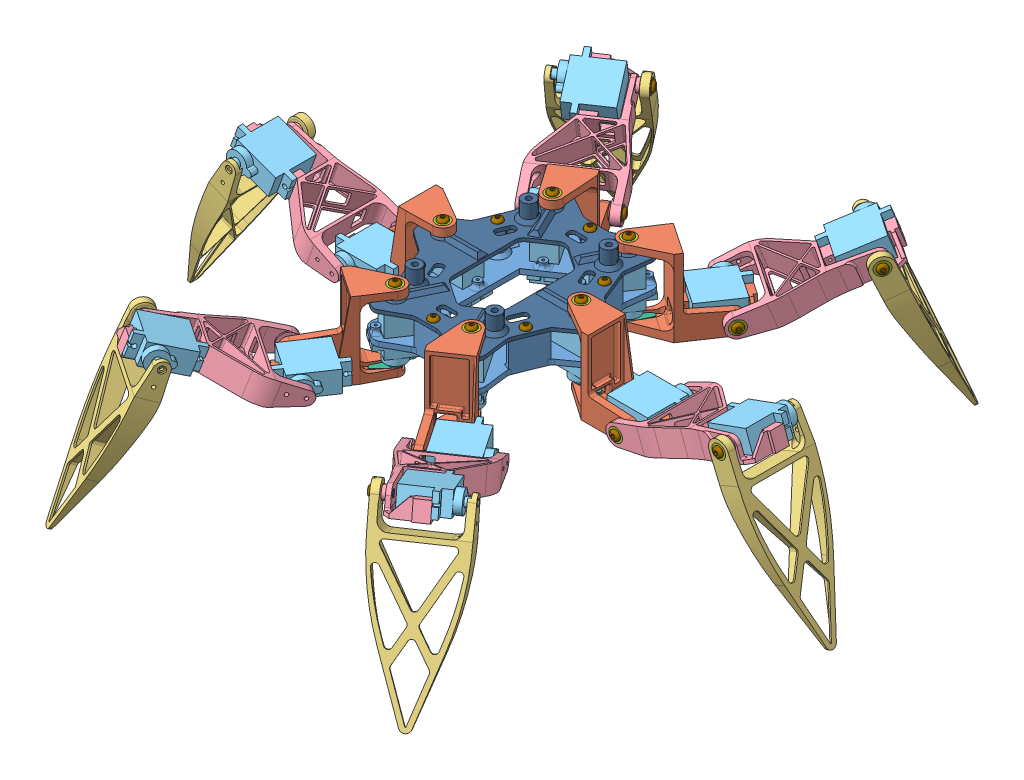
SolidWorks assembly Assem1, configuration Default. Lengths in mm.
Overall size (377.21 111.85 364.23).
104 component instances, 10 part files, 33 mates.
Components (placement in the parent):
- Base-1: Base [Default] at (36.3736 62.9905 92.2732) size (103.38 17 115.92)
- leg-1: leg [Default] at (45.8223 35.6523 69.1252) size (170.91 110.5 47.15)
  - hip-1: hip [Default] at (51.2432 8.3382 17.148) size (59.75 45 23)
  - shin-1: shin [Default] at (173.3847 -53.1633 22.948) x (0 0 1) z (-0.920457 -0.390844 0) size (45 106 12.27)
  - thigh-1: thigh [Default] at (116.4644 23.5871 17.948) x (0.93934 0.342988 0) z (0 0 1) size (82.75 14 45)
  - MG90S Servo-1: MG90S Servo [Default] at (129.6036 37.1675 33.948) x (0.93934 0.342988 0) z (-0.342988 0.93934 0) size (34 31 12.5)
  - MG90S Servo-2: MG90S Servo [Default] at (68.2432 16.5882 33.148) x (1 0 0) z (0 1 0) size (34 31 12.5)
  - MG90S Servo-4: MG90S Servo [Default] at (25.2432 43.3382 23.148) x (1 0 0) z (0 0 -1) size (34 31 12.5)
  - servo horn-1: servo horn [Default] at (31.2432 10.8382 23.148) size (14.5 4.5 6)
  - Bearing-1: Bearing [Default] at (73.2432 16.5882 40.948) x (1 0 0) z (0 -1 0) size (8 4 8)
  - threaded insert-1: threaded insert [Default] at (73.2432 16.5882 35.448) x (1 0 0) z (0 -1 0) size (4 4.7 4)
  - threaded insert-2: threaded insert [Default] at (134.3003 38.8824 36.248) x (0.987351 0.158553 0) z (0.158553 -0.987351 0) size (4 4.7 4)
  - Bearing-2: Bearing [Default] at (31.2432 49.3382 23.148) x (0.930301 0 -0.366796) z (0.366796 0 0.930301) size (8 4 8)
  - Bearing-5: Bearing [Default] at (134.3003 38.8824 41.448) x (0.766992 0.641657 0) z (0.641657 -0.766992 0) size (8 4 8)
  - m3x8 button-1: m3x8 button [Default] at (73.2432 16.5882 46.598) x (0 0 -1) z (0.234843 0.972033 0) size (9.65 5.7 5.7)
  - m3x8 button-2: m3x8 button [Default] at (134.3003 38.8824 47.098) x (0 0 -1) z (0.077754 0.996973 0) size (9.65 5.7 5.7)
  - m3x8 button-4: m3x8 button [Default] at (31.2432 54.9882 23.148) x (0 -1 0) z (-0.515031 0 -0.857172) size (9.65 5.7 5.7)
- Top-1: Top [Default] at (36.3236 79.9905 92.3982) size (103.88 12 115.92)
- m3x8 button-1: m3x8 button [Default] at (67.7613 83.6405 115.5337) x (0 -1 0) z (-0.034129 0 0.999417) size (9.65 5.7 5.7)
- m3x8 button-2: m3x8 button [Default] at (36.3236 83.6405 138.3982) x (0 -1 0) z (0.154828 0 0.987941) size (9.65 5.7 5.7)
- m3x8 button-3: m3x8 button [Default] at (4.8859 83.6405 115.5337) x (0 -1 0) z (0.364161 0 0.931336) size (9.65 5.7 5.7)
- m3x8 button-4: m3x8 button [Default] at (4.8859 83.6405 69.2627) x (0 -1 0) z (0.572348 0 0.820011) size (9.65 5.7 5.7)
- m3x8 button-5: m3x8 button [Default] at (36.3236 83.6405 46.3982) x (0 -1 0) z (0.751604 0 0.659615) size (9.65 5.7 5.7)
- m3x8 button-6: m3x8 button [Default] at (67.7613 83.6405 69.2627) x (0 -1 0) z (0.880548 0 0.473957) size (9.65 5.7 5.7)
- leg-2: leg [Default] at (60.4579 35.6523 99.6313) x (0.560629 0 0.828067) z (-0.828067 0 0.560629) size (170.91 110.5 47.15)
  - hip-1: hip [Default] at (51.2432 8.3382 17.148) size (59.75 45 23)
  - shin-1: shin [Default] at (173.3847 -53.1633 22.948) x (0 0 1) z (-0.920457 -0.390844 0) size (45 106 12.27)
  - thigh-1: thigh [Default] at (116.4644 23.5871 17.948) x (0.93934 0.342988 0) z (0 0 1) size (82.75 14 45)
  - MG90S Servo-1: MG90S Servo [Default] at (129.6036 37.1675 33.948) x (0.93934 0.342988 0) z (-0.342988 0.93934 0) size (34 31 12.5)
  - MG90S Servo-2: MG90S Servo [Default] at (68.2432 16.5882 33.148) x (1 0 0) z (0 1 0) size (34 31 12.5)
  - MG90S Servo-4: MG90S Servo [Default] at (25.2432 43.3382 23.148) x (1 0 0) z (0 0 -1) size (34 31 12.5)
  - servo horn-1: servo horn [Default] at (31.2432 10.8382 23.148) size (14.5 4.5 6)
  - Bearing-1: Bearing [Default] at (73.2432 16.5882 40.948) x (1 0 0) z (0 -1 0) size (8 4 8)
  - threaded insert-1: threaded insert [Default] at (73.2432 16.5882 35.448) x (1 0 0) z (0 -1 0) size (4 4.7 4)
  - threaded insert-2: threaded insert [Default] at (134.3003 38.8824 36.248) x (0.987351 0.158553 0) z (0.158553 -0.987351 0) size (4 4.7 4)
  - Bearing-2: Bearing [Default] at (31.2432 49.3382 23.148) x (0.930301 0 -0.366796) z (0.366796 0 0.930301) size (8 4 8)
  - Bearing-5: Bearing [Default] at (134.3003 38.8824 41.448) x (0.766992 0.641657 0) z (0.641657 -0.766992 0) size (8 4 8)
  - m3x8 button-1: m3x8 button [Default] at (73.2432 16.5882 46.598) x (0 0 -1) z (0.234843 0.972033 0) size (9.65 5.7 5.7)
  - m3x8 button-2: m3x8 button [Default] at (134.3003 38.8824 47.098) x (0 0 -1) z (0.077754 0.996973 0) size (9.65 5.7 5.7)
  - m3x8 button-4: m3x8 button [Default] at (31.2432 54.9882 23.148) x (0 -1 0) z (-0.515031 0 -0.857172) size (9.65 5.7 5.7)
- leg-5: leg [Default] at (50.6255 35.6523 125.5862) x (-0.560629 0 0.828067) z (-0.828067 0 -0.560629) size (170.91 110.5 47.15)
  - hip-1: hip [Default] at (51.2432 8.3382 17.148) size (59.75 45 23)
  - shin-1: shin [Default] at (173.3847 -53.1633 22.948) x (0 0 1) z (-0.920457 -0.390844 0) size (45 106 12.27)
  - thigh-1: thigh [Default] at (116.4644 23.5871 17.948) x (0.93934 0.342988 0) z (0 0 1) size (82.75 14 45)
  - MG90S Servo-1: MG90S Servo [Default] at (129.6036 37.1675 33.948) x (0.93934 0.342988 0) z (-0.342988 0.93934 0) size (34 31 12.5)
  - MG90S Servo-2: MG90S Servo [Default] at (68.2432 16.5882 33.148) x (1 0 0) z (0 1 0) size (34 31 12.5)
  - MG90S Servo-4: MG90S Servo [Default] at (25.2432 43.3382 23.148) x (1 0 0) z (0 0 -1) size (34 31 12.5)
  - servo horn-1: servo horn [Default] at (31.2432 10.8382 23.148) size (14.5 4.5 6)
  - Bearing-1: Bearing [Default] at (73.2432 16.5882 40.948) x (1 0 0) z (0 -1 0) size (8 4 8)
  - threaded insert-1: threaded insert [Default] at (73.2432 16.5882 35.448) x (1 0 0) z (0 -1 0) size (4 4.7 4)
  - threaded insert-2: threaded insert [Default] at (134.3003 38.8824 36.248) x (0.987351 0.158553 0) z (0.158553 -0.987351 0) size (4 4.7 4)
  - Bearing-2: Bearing [Default] at (31.2432 49.3382 23.148) x (0.930301 0 -0.366796) z (0.366796 0 0.930301) size (8 4 8)
  - Bearing-5: Bearing [Default] at (134.3003 38.8824 41.448) x (0.766992 0.641657 0) z (0.641657 -0.766992 0) size (8 4 8)
  - m3x8 button-1: m3x8 button [Default] at (73.2432 16.5882 46.598) x (0 0 -1) z (0.234843 0.972033 0) size (9.65 5.7 5.7)
  - m3x8 button-2: m3x8 button [Default] at (134.3003 38.8824 47.098) x (0 0 -1) z (0.077754 0.996973 0) size (9.65 5.7 5.7)
  - m3x8 button-4: m3x8 button [Default] at (31.2432 54.9882 23.148) x (0 -1 0) z (-0.515031 0 -0.857172) size (9.65 5.7 5.7)
- leg-6: leg [Default] at (26.9249 35.6523 115.4212) x (-1 0 0) z (0 0 -1) size (170.91 110.5 47.15)
  - hip-1: hip [Default] at (51.2432 8.3382 17.148) size (59.75 45 23)
  - shin-1: shin [Default] at (173.3847 -53.1633 22.948) x (0 0 1) z (-0.920457 -0.390844 0) size (45 106 12.27)
  - thigh-1: thigh [Default] at (116.4644 23.5871 17.948) x (0.93934 0.342988 0) z (0 0 1) size (82.75 14 45)
  - MG90S Servo-1: MG90S Servo [Default] at (129.6036 37.1675 33.948) x (0.93934 0.342988 0) z (-0.342988 0.93934 0) size (34 31 12.5)
  - MG90S Servo-2: MG90S Servo [Default] at (68.2432 16.5882 33.148) x (1 0 0) z (0 1 0) size (34 31 12.5)
  - MG90S Servo-4: MG90S Servo [Default] at (25.2432 43.3382 23.148) x (1 0 0) z (0 0 -1) size (34 31 12.5)
  - servo horn-1: servo horn [Default] at (31.2432 10.8382 23.148) size (14.5 4.5 6)
  - Bearing-1: Bearing [Default] at (73.2432 16.5882 40.948) x (1 0 0) z (0 -1 0) size (8 4 8)
  - threaded insert-1: threaded insert [Default] at (73.2432 16.5882 35.448) x (1 0 0) z (0 -1 0) size (4 4.7 4)
  - threaded insert-2: threaded insert [Default] at (134.3003 38.8824 36.248) x (0.987351 0.158553 0) z (0.158553 -0.987351 0) size (4 4.7 4)
  - Bearing-2: Bearing [Default] at (31.2432 49.3382 23.148) x (0.930301 0 -0.366796) z (0.366796 0 0.930301) size (8 4 8)
  - Bearing-5: Bearing [Default] at (134.3003 38.8824 41.448) x (0.766992 0.641657 0) z (0.641657 -0.766992 0) size (8 4 8)
  - m3x8 button-1: m3x8 button [Default] at (73.2432 16.5882 46.598) x (0 0 -1) z (0.234843 0.972033 0) size (9.65 5.7 5.7)
  - m3x8 button-2: m3x8 button [Default] at (134.3003 38.8824 47.098) x (0 0 -1) z (0.077754 0.996973 0) size (9.65 5.7 5.7)
  - m3x8 button-4: m3x8 button [Default] at (31.2432 54.9882 23.148) x (0 -1 0) z (-0.515031 0 -0.857172) size (9.65 5.7 5.7)
- leg-7: leg [Default] at (12.2893 35.6523 84.9151) x (-0.560629 0 -0.828067) z (0.828067 0 -0.560629) size (170.91 110.5 47.15)
  - hip-1: hip [Default] at (51.2432 8.3382 17.148) size (59.75 45 23)
  - shin-1: shin [Default] at (173.3847 -53.1633 22.948) x (0 0 1) z (-0.920457 -0.390844 0) size (45 106 12.27)
  - thigh-1: thigh [Default] at (116.4644 23.5871 17.948) x (0.93934 0.342988 0) z (0 0 1) size (82.75 14 45)
  - MG90S Servo-1: MG90S Servo [Default] at (129.6036 37.1675 33.948) x (0.93934 0.342988 0) z (-0.342988 0.93934 0) size (34 31 12.5)
  - MG90S Servo-2: MG90S Servo [Default] at (68.2432 16.5882 33.148) x (1 0 0) z (0 1 0) size (34 31 12.5)
  - MG90S Servo-4: MG90S Servo [Default] at (25.2432 43.3382 23.148) x (1 0 0) z (0 0 -1) size (34 31 12.5)
  - servo horn-1: servo horn [Default] at (31.2432 10.8382 23.148) size (14.5 4.5 6)
  - Bearing-1: Bearing [Default] at (73.2432 16.5882 40.948) x (1 0 0) z (0 -1 0) size (8 4 8)
  - threaded insert-1: threaded insert [Default] at (73.2432 16.5882 35.448) x (1 0 0) z (0 -1 0) size (4 4.7 4)
  - threaded insert-2: threaded insert [Default] at (134.3003 38.8824 36.248) x (0.987351 0.158553 0) z (0.158553 -0.987351 0) size (4 4.7 4)
  - Bearing-2: Bearing [Default] at (31.2432 49.3382 23.148) x (0.930301 0 -0.366796) z (0.366796 0 0.930301) size (8 4 8)
  - Bearing-5: Bearing [Default] at (134.3003 38.8824 41.448) x (0.766992 0.641657 0) z (0.641657 -0.766992 0) size (8 4 8)
  - m3x8 button-1: m3x8 button [Default] at (73.2432 16.5882 46.598) x (0 0 -1) z (0.234843 0.972033 0) size (9.65 5.7 5.7)
  - m3x8 button-2: m3x8 button [Default] at (134.3003 38.8824 47.098) x (0 0 -1) z (0.077754 0.996973 0) size (9.65 5.7 5.7)
  - m3x8 button-4: m3x8 button [Default] at (31.2432 54.9882 23.148) x (0 -1 0) z (-0.515031 0 -0.857172) size (9.65 5.7 5.7)
- leg-8: leg [Default] at (22.1217 35.6523 58.9602) x (0.560629 0 -0.828067) z (0.828067 0 0.560629) size (170.91 110.5 47.15)
  - hip-1: hip [Default] at (51.2432 8.3382 17.148) size (59.75 45 23)
  - shin-1: shin [Default] at (173.3847 -53.1633 22.948) x (0 0 1) z (-0.920457 -0.390844 0) size (45 106 12.27)
  - thigh-1: thigh [Default] at (116.4644 23.5871 17.948) x (0.93934 0.342988 0) z (0 0 1) size (82.75 14 45)
  - MG90S Servo-1: MG90S Servo [Default] at (129.6036 37.1675 33.948) x (0.93934 0.342988 0) z (-0.342988 0.93934 0) size (34 31 12.5)
  - MG90S Servo-2: MG90S Servo [Default] at (68.2432 16.5882 33.148) x (1 0 0) z (0 1 0) size (34 31 12.5)
  - MG90S Servo-4: MG90S Servo [Default] at (25.2432 43.3382 23.148) x (1 0 0) z (0 0 -1) size (34 31 12.5)
  - servo horn-1: servo horn [Default] at (31.2432 10.8382 23.148) size (14.5 4.5 6)
  - Bearing-1: Bearing [Default] at (73.2432 16.5882 40.948) x (1 0 0) z (0 -1 0) size (8 4 8)
  - threaded insert-1: threaded insert [Default] at (73.2432 16.5882 35.448) x (1 0 0) z (0 -1 0) size (4 4.7 4)
  - threaded insert-2: threaded insert [Default] at (134.3003 38.8824 36.248) x (0.987351 0.158553 0) z (0.158553 -0.987351 0) size (4 4.7 4)
  - Bearing-2: Bearing [Default] at (31.2432 49.3382 23.148) x (0.930301 0 -0.366796) z (0.366796 0 0.930301) size (8 4 8)
  - Bearing-5: Bearing [Default] at (134.3003 38.8824 41.448) x (0.766992 0.641657 0) z (0.641657 -0.766992 0) size (8 4 8)
  - m3x8 button-1: m3x8 button [Default] at (73.2432 16.5882 46.598) x (0 0 -1) z (0.234843 0.972033 0) size (9.65 5.7 5.7)
  - m3x8 button-2: m3x8 button [Default] at (134.3003 38.8824 47.098) x (0 0 -1) z (0.077754 0.996973 0) size (9.65 5.7 5.7)
  - m3x8 button-4: m3x8 button [Default] at (31.2432 54.9882 23.148) x (0 -1 0) z (-0.515031 0 -0.857172) size (9.65 5.7 5.7)
Mates (geometry in assembly coordinates):
- Concentric1: concentric anti-aligned: cylinder of Base-1 through (56.5655 55.9905 92.2732) axis (0 1 0) radius 0.75; cylinder of leg-1/MG90S Servo-4 through (56.5655 63.9905 92.2732) axis (0 -1 0) radius 1.25
- Coincident1: coincident anti-aligned: plane of Base-1 through (36.3736 62.9905 92.2732) normal (0 -1 0); plane of leg-1/MG90S Servo-4 through (54.0655 62.9905 86.0232) normal (0 1 0)
- Parallel1: parallel anti-aligned: plane of Base-1 through (36.3736 29.3086 98.7732) normal (0 0 -1); plane of leg-1/MG90S Servo-4 through (59.0655 54.9905 98.5232) normal (0 0 1)
- Concentric2: concentric anti-aligned: cylinder of Base-1 through (67.7613 79.9905 115.5337) axis (0 -1 0) radius 2; cylinder of Top-1 through (67.7613 71.9905 115.5337) axis (0 1 0) radius 1.6
- Parallel2: parallel anti-aligned: cylinder of Base-1 through (36.3736 79.9905 46.2732) axis (0 -1 0) radius 2; cylinder of Top-1 through (36.3236 71.9905 46.3982) axis (0 1 0) radius 1.6
- Coincident3: coincident anti-aligned: plane of Base-1 through (36.3736 79.9905 92.2732) normal (0 1 0); plane of Top-1 through (36.3236 79.9905 92.3982) normal (0 -1 0)
- Coincident4: coincident anti-aligned: plane of Top-1 through (36.3236 81.9905 92.3982) normal (0 1 0); plane of m3x8 button-1 through (67.8125 81.9905 114.0346) normal (0 -1 0)
- Concentric4: concentric anti-aligned: cylinder of Top-1 through (67.7613 71.9905 115.5337) axis (0 1 0) radius 1.6; cylinder of m3x8 button-1 through (67.7613 83.6405 115.5337) axis (0 -1 0) radius 2.85
- Coincident5: coincident anti-aligned: plane of Top-1 through (36.3236 81.9905 92.3982) normal (0 1 0); plane of m3x8 button-2 through (36.0914 81.9905 136.9163) normal (0 -1 0)
- Concentric5: concentric anti-aligned: cylinder of Top-1 through (36.3236 71.9905 138.3982) axis (0 1 0) radius 1.6; cylinder of m3x8 button-2 through (36.3236 83.6405 138.3982) axis (0 -1 0) radius 2.85
- Coincident6: coincident anti-aligned: plane of Top-1 through (36.3236 81.9905 92.3982) normal (0 1 0); plane of m3x8 button-3 through (4.3397 81.9905 114.1367) normal (0 -1 0)
- Concentric6: concentric anti-aligned: cylinder of Top-1 through (4.8859 71.9905 115.5337) axis (0 1 0) radius 1.6; cylinder of m3x8 button-3 through (4.8859 83.6405 115.5337) axis (0 -1 0) radius 2.85
- Coincident7: coincident anti-aligned: plane of Top-1 through (36.3236 81.9905 92.3982) normal (0 1 0); plane of m3x8 button-4 through (4.0274 81.9905 68.0327) normal (0 -1 0)
- Concentric7: concentric anti-aligned: cylinder of Top-1 through (4.8859 71.9905 69.2627) axis (0 1 0) radius 1.6; cylinder of m3x8 button-4 through (4.8859 83.6405 69.2627) axis (0 -1 0) radius 2.85
- Coincident8: coincident anti-aligned: plane of Top-1 through (36.3236 81.9905 92.3982) normal (0 1 0); plane of m3x8 button-5 through (35.1962 81.9905 45.4088) normal (0 -1 0)
- Concentric8: concentric anti-aligned: cylinder of Top-1 through (36.3236 71.9905 46.3982) axis (0 1 0) radius 1.6; cylinder of m3x8 button-5 through (36.3236 83.6405 46.3982) axis (0 -1 0) radius 2.85
- Coincident9: coincident anti-aligned: plane of Top-1 through (36.3236 81.9905 92.3982) normal (0 1 0); plane of m3x8 button-6 through (66.4404 81.9905 68.5518) normal (0 -1 0)
- Concentric9: concentric anti-aligned: cylinder of Top-1 through (67.7613 71.9905 69.2627) axis (0 1 0) radius 1.6; cylinder of m3x8 button-6 through (67.7613 83.6405 69.2627) axis (0 -1 0) radius 2.85
- Concentric10: concentric anti-aligned: cylinder of Base-1 through (47.3127 55.9905 121.5048) axis (0 1 0) radius 0.75; cylinder of leg-2/MG90S Servo-4 through (47.3127 63.9905 121.5048) axis (0 -1 0) radius 1.25
- Coincident11: coincident anti-aligned: plane of Base-1 through (36.3736 62.9905 92.2732) normal (0 -1 0); plane of leg-2/MG90S Servo-4 through (51.0866 62.9905 115.9307) normal (0 1 0)
- Parallel3: parallel anti-aligned: plane of Base-1 through (56.994 26.6108 146.9525) normal (0.828067 0 -0.560629); plane of leg-2/MG90S Servo-4 through (43.5389 54.9905 127.0789) normal (-0.828067 0 0.560629)
- Concentric13: concentric aligned: cylinder of Base-1 through (25.4345 68.9905 121.5048) axis (0 -1 0) radius 2.25; cylinder of leg-5/MG90S Servo-4 through (25.4345 63.9905 121.5048) axis (0 -1 0) radius 1.25
- Coincident14: coincident anti-aligned: plane of Base-1 through (36.3736 62.9905 92.2732) normal (0 -1 0); plane of leg-5/MG90S Servo-4 through (32.0115 62.9905 122.9386) normal (0 1 0)
- Parallel7: parallel aligned: plane of Base-1 through (15.7532 26.6108 146.9525) normal (-0.828067 0 -0.560629); plane of leg-5/MG90S Servo-4 through (18.8575 54.9905 120.0711) normal (-0.828067 0 -0.560629)
- Coincident15: coincident anti-aligned: plane of Base-1 through (36.3736 62.9905 92.2732) normal (0 -1 0); plane of leg-6/MG90S Servo-4 through (18.6817 62.9905 98.5232) normal (0 1 0)
- Concentric14: concentric aligned: cylinder of Base-1 through (16.1817 68.9905 92.2732) axis (0 -1 0) radius 2.25; cylinder of leg-6/MG90S Servo-4 through (16.1817 63.9905 92.2732) axis (0 -1 0) radius 1.25
- Parallel8: parallel aligned: plane of Base-1 through (36.3736 29.3086 98.7732) normal (0 0 -1); plane of leg-6/MG90S Servo-4 through (13.6817 54.9905 86.0232) normal (0 0 -1)
- Coincident16: coincident anti-aligned: plane of Base-1 through (36.3736 62.9905 92.2732) normal (0 -1 0); plane of leg-7/MG90S Servo-4 through (21.6606 62.9905 68.6157) normal (0 1 0)
- Concentric15: concentric aligned: cylinder of Base-1 through (25.4345 68.9905 63.0416) axis (0 -1 0) radius 2.25; cylinder of leg-7/MG90S Servo-4 through (25.4345 63.9905 63.0416) axis (0 -1 0) radius 1.25
- Parallel9: parallel anti-aligned: plane of Base-1 through (15.7532 26.6108 37.5938) normal (-0.828067 0 0.560629); plane of leg-7/MG90S Servo-4 through (29.2083 54.9905 57.4675) normal (0.828067 0 -0.560629)
- Coincident17: coincident anti-aligned: plane of Base-1 through (36.3736 62.9905 92.2732) normal (0 -1 0); plane of leg-8/MG90S Servo-4 through (40.7357 62.9905 61.6078) normal (0 1 0)
- Concentric16: concentric aligned: cylinder of Base-1 through (47.3127 68.9905 63.0416) axis (0 -1 0) radius 2.25; cylinder of leg-8/MG90S Servo-4 through (47.3127 63.9905 63.0416) axis (0 -1 0) radius 1.25
- Parallel10: parallel anti-aligned: plane of Base-1 through (64.1767 26.6108 49.2811) normal (-0.828067 0 -0.560629); plane of leg-8/MG90S Servo-4 through (53.8897 54.9905 64.4753) normal (0.828067 0 0.560629)
